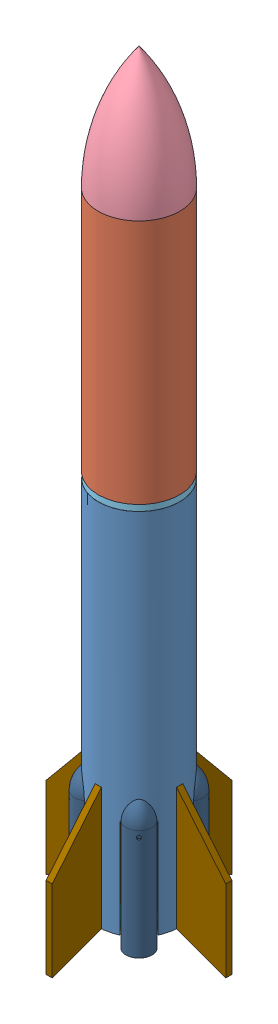
SolidWorks assembly Rocket, configuration Default. Lengths in mm.
Overall size (146.32 619.56 146.32).
16 component instances, 10 part files, 28 mates.
Components (placement in the parent):
- Booster Tube-1: Booster Tube [Default] at (0 150 0) size (66.32 300 66.32)
- Electronics Bay-1: Electronics Bay [Default] at (0 405 0) x (-0.134824 0 -0.99087) z (0.99087 0 -0.134824) size (66.32 200 66.32)
- Lower Electronics Coupler-1: Lower Electronics Coupler [Default] at (0 290 0) x (-0.134824 0 -0.99087) z (0.99087 0 -0.134824) size (64.07 5.07 64.07)
- Nose Cone-1: Nose Cone [Default] at (0 505 0) x (-0.134824 0 -0.99087) z (0.99087 0 -0.134824) size (66.32 120 66.32)
- Upper Electronics Coupler-1: Upper Electronics Coupler [Default] at (0 302.5 0) x (-0.134824 0 -0.99087) z (0.99087 0 -0.134824) size (66 20 66)
- Lower Centering Ring-1: Lower Centering Ring [Default] at (0 7.5 0) x (0.707107 0 0.707107) z (-0.707107 0 0.707107) size (60.76 5 60.76)
- Motor Tube-1: Motor Tube [Default] at (0 50 0) size (33 120 33)
- Upper Centering Ring-1: Upper Centering Ring [Default] at (0 82.5 0) x (0.976616 0 0.214991) z (-0.214991 0 0.976616) size (64.27 5 64.27)
- Fin-2: Fin [Default] at (33.16 100 0) x (0 -1 0) z (-1 0 0) size (114.56 5 57.16)
- Fin-3: Fin [Default] at (0 100 33.16) x (0 -1 0) z (0 0 -1) size (114.56 5 57.16)
- Fin-4: Fin [Default] at (-33.16 100 0) x (0 -1 0) z (1 0 0) size (114.56 5 57.16)
- Fin-5: Fin [Default] at (0 100 -33.16) x (0 -1 0) z (0 0 1) size (114.56 5 57.16)
- Small Motor Tube-1: Small Motor Tube [Default] at (21.0364 35 21.0364) x (-0.707107 0 -0.707107) z (0.707107 0 -0.707107) size (21 108.48 23.36)
- Small Motor Tube-2: Small Motor Tube [Default] at (-21.0364 35 21.0364) x (0.707107 0 -0.707107) z (0.707107 0 0.707107) size (21 108.48 23.36)
- Small Motor Tube-3: Small Motor Tube [Default] at (-21.0364 35 -21.0364) x (0.707107 0 0.707107) z (-0.707107 0 0.707107) size (21 108.48 23.36)
- Small Motor Tube-4: Small Motor Tube [Default] at (21.0364 35 -21.0364) x (-0.707107 0 0.707107) z (-0.707107 0 -0.707107) size (21 108.48 23.36)
Mates (geometry in assembly coordinates):
- Concentric1: concentric aligned: cylinder of Electronics Bay-1 through (0 505 0) axis (0 -1 0) radius 33.16; cylinder of Upper Electronics Coupler-1 through (0 312.5 0) axis (0 -1 0) radius 32.035
- Concentric2: concentric aligned: cylinder of Lower Electronics Coupler-1 through (0 292.5 0) axis (0 -1 0) radius 32.035; cylinder of Upper Electronics Coupler-1 through (0 312.5 0) axis (0 -1 0) radius 32.035
- Coincident1: coincident aligned: plane of Lower Electronics Coupler-1 through (-6.4742 287.5 -26.8876) normal (-0.134824 0 -0.99087); plane of Upper Electronics Coupler-1 through (-0.9452 287.5 -27.6399) normal (-0.134824 0 -0.99087)
- Concentric3: concentric aligned: cylinder of Booster Tube-1 through (0 300 0) axis (0 -1 0) radius 33.16; cylinder of Lower Electronics Coupler-1 through (0 292.5 0) axis (0 -1 0) radius 32.035
- Concentric4: concentric aligned: cylinder of Electronics Bay-1 through (0 505 0) axis (0 -1 0) radius 33.16; cylinder of Nose Cone-1 through (0 590 0) axis (0 -1 0) radius 32.385
- Coincident2: coincident anti-aligned: plane of Electronics Bay-1 through (0 505 0) normal (0 1 0); plane of Nose Cone-1 through (-4.3663 505 -32.0893) normal (0 -1 0)
- Distance2: distance = 7.5 mm aligned: plane of Lower Electronics Coupler-1 through (0 292.5 0) normal (0 1 0); plane of Booster Tube-1 through (0 300 0) normal (0 1 0)
- LimitDistance1: limit distance = 0 mm anti-aligned: plane of Upper Electronics Coupler-1 through (0 292.5 0) normal (0 -1 0); plane of Lower Electronics Coupler-1 through (0 292.5 0) normal (0 1 0)
- Concentric5: concentric aligned: cylinder of Motor Tube-1 through (0 110 0) axis (0 -1 0) radius 16.5; cylinder of Upper Centering Ring-1 through (0 85 0) axis (0 -1 0) radius 16.25
- Concentric6: concentric aligned: cylinder of Lower Centering Ring-1 through (0 10 0) axis (0 -1 0) radius 16.25; cylinder of Motor Tube-1 through (0 110 0) axis (0 -1 0) radius 16.5
- Concentric7: concentric aligned: cylinder of Booster Tube-1 through (0 300 0) axis (0 -1 0) radius 33.16; cylinder of Upper Centering Ring-1 through (0 85 0) axis (0 -1 0) radius 32.135
- Distance4: distance = 5 mm aligned: plane of Lower Centering Ring-1 through (0 5 0) normal (0 -1 0); plane of Booster Tube-1 through (0 0 0) normal (0 -1 0)
- Distance5: distance = 80 mm aligned: plane of Upper Centering Ring-1 through (0 80 0) normal (0 -1 0); plane of Booster Tube-1 through (0 0 0) normal (0 -1 0)
- Distance6: distance = 10 mm aligned: plane of Motor Tube-1 through (0 -10 0) normal (0 -1 0); plane of Booster Tube-1 through (0 0 0) normal (0 -1 0)
- Coincident10: coincident aligned: plane of Booster Tube-1 through (0 150 0) normal (1 0 0); plane of assembly through (0 0 0) normal (1 0 0)
- Coincident12: coincident aligned: plane of Booster Tube-1 through (0 150 0) normal (0 0 1); plane of assembly through (0 0 0) normal (0 0 1)
- Tangent2: tangent anti-aligned: cylinder of Booster Tube-1 through (0 300 0) axis (0 -1 0) radius 33.16; plane of Fin-2 through (33.16 100 2.5) normal (-1 0 0)
- Coincident13: coincident aligned: plane of Fin-2 through (33.16 100 0) normal (0 0 1); plane of assembly through (0 0 0) normal (0 0 1)
- Coincident14: coincident: plane of Booster Tube-1 through (0 0 0) normal (0 -1 0); plane of assembly through (0 0 0) normal (0 1 0)
- Coincident15: coincident anti-aligned: plane of Upper Centering Ring-1 through (0 80 0) normal (0 -1 0); plane of Fin-2 through (33.16 80 2.5) normal (0 1 0)
- Concentric8: concentric aligned: cylinder of Booster Tube-1 through (0 300 0) axis (0 -1 0) radius 33.16; cylinder of Motor Tube-1 through (0 110 0) axis (0 -1 0) radius 16.5
- Concentric9: concentric: cylinder of assembly; cylinder of Lower Centering Ring-1 through (0 10 0) axis (0 -1 0) radius 32.135; cylinder of Upper Centering Ring-1 through (0 85 0) axis (0 -1 0) radius 32.135
- Concentric10: concentric anti-aligned: cylinder of Lower Centering Ring-1 through (21.0364 5 21.0364) axis (0 1 0) radius 10.5; cylinder of Small Motor Tube-1 through (21.0364 80 21.0364) axis (0 -1 0) radius 10.5
- Coincident17: coincident aligned: plane of Motor Tube-1 through (0 -10 0) normal (0 -1 0); plane of Small Motor Tube-1 through (21.0364 -10 21.0364) normal (0 -1 0)
- Coincident18: coincident anti-aligned: plane of Lower Centering Ring-1 through (0 7.5 0) normal (-0.707107 0 0.707107); plane of assembly through (0 0 0) normal (0.707107 0 -0.707107)
- Concentric11: concentric aligned: cylinder of Booster Tube-1 through (0 300 0) axis (0 -1 0) radius 33.16; cylinder of Small Motor Tube-1 through (0 100 0) axis (0 -1 0) radius 33.16
- Parallel2: parallel aligned: cylinder of Lower Centering Ring-1 through (22.9629 5 3.6428) axis (0 1 0) radius 5; cylinder of Upper Centering Ring-1 through (23.6268 80 5.2012) axis (0 1 0) radius 1.5
- Coincident19: coincident anti-aligned: plane of Electronics Bay-1 through (0 305 0) normal (0 -1 0); plane of Upper Electronics Coupler-1 through (0 305 0) normal (0 1 0)
